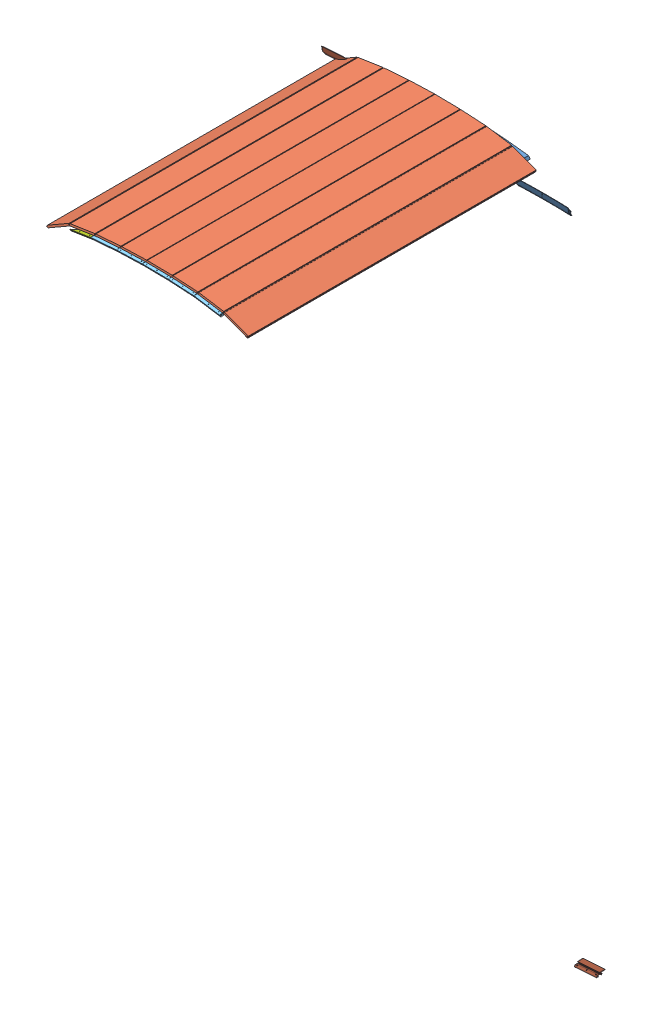
SolidWorks assembly Rear LED Covers, configuration Default. Lengths in mm.
Overall size (2450.92 4696.16 2251.77).
49 component instances, 13 part files, 81 mates.
Components (placement in the parent):
- Rear Ceiling LED Assembly-1: Rear Ceiling LED Assembly [Default] at origin size (1270 56.34 106.68)
- Floor Board-10: Floor Board [Default] at (-117.3306 4.4304 1117.6) x (0.999454 0.033052 0) z (0 0 1) size (195.54 15.11 2133.6)
- Floor Board-11: Floor Board [Default] at (71.8879 6.0598 1117.6) x (0.999875 -0.015835 0) z (0 0 1) size (195.54 15.11 2133.6)
- Floor Board-12: Floor Board [Default] at (262.1828 -1.0885 1117.6) x (0.998261 -0.058943 0) z (0 0 1) size (195.54 15.11 2133.6)
- Floor Board-13: Floor Board [Default] at (453.3637 -21.8246 1117.6) x (0.987717 -0.156253 0) z (0 0 1) size (195.54 15.11 2133.6)
- Floor Board-14: Floor Board [Default] at (-307.4744 -6.0039 1117.6) x (0.99709 0.07623 0) z (0 0 1) size (195.54 15.11 2133.6)
- Floor Board-15: Floor Board [Default] at (-498.2964 -27.9601 1117.6) x (0.988363 0.152114 0) z (0 0 1) size (195.54 15.11 2133.6)
- Floor Board-16: Floor Board [Default] at (638.9233 -71.1917 1117.6) x (0.934506 -0.355948 0) z (0 0 1) size (195.54 15.11 2133.6)
- Floor Board-17: Floor Board [Default] at (-676.3258 -89.879 1117.6) x (0.866563 0.499069 0) z (0 0 1) size (195.54 15.11 2133.6)
- Ceiling LED Mount V1-1: Ceiling LED Mount V1 [Default] at (-574.2075 -55.8979 171.45) x (-0.988363 -0.152114 0) z (0 0 -1) size (29.58 14.17 190.5)
- Ceiling LED Mount V1-2: Ceiling LED Mount V1 [Default] at (530.2435 -50.2519 171.45) x (-0.987717 0.156253 0) z (0 0 -1) size (29.58 14.17 190.5)
- Aclorol LED Neon Rope Lights Addressable LED Strip-1: Aclorol LED Neon Rope Lights Addressable LED Strip [Default] at (133.4826 -131.6632 -32.4083) size (381 11.94 6.05)
- Ceiling LED Mount V1-3: Ceiling LED Mount V1 [Default] at (530.2435 -50.2519 355.6) x (-0.987717 0.156253 0) z (0 0 -1) size (29.58 14.17 190.5)
- Ceiling LED Mount V1-4: Ceiling LED Mount V1 [Default] at (530.2435 -50.2519 539.75) x (-0.987717 0.156253 0) z (0 0 -1) size (29.58 14.17 190.5)
- Ceiling LED Mount V1-5: Ceiling LED Mount V1 [Default] at (530.2435 -50.2519 723.9) x (-0.987717 0.156253 0) z (0 0 -1) size (29.58 14.17 190.5)
- Ceiling LED Mount V1-6: Ceiling LED Mount V1 [Default] at (530.2435 -50.2519 908.05) x (-0.987717 0.156253 0) z (0 0 -1) size (29.58 14.17 190.5)
- Ceiling LED Mount V1-7: Ceiling LED Mount V1 [Default] at (530.2435 -50.2519 1092.2) x (-0.987717 0.156253 0) z (0 0 -1) size (29.58 14.17 190.5)
- Ceiling LED Mount V1-8: Ceiling LED Mount V1 [Default] at (530.2435 -50.2519 1276.35) x (-0.987717 0.156253 0) z (0 0 -1) size (29.58 14.17 190.5)
- Ceiling LED Mount V1-9: Ceiling LED Mount V1 [Default] at (530.2435 -50.2519 1460.5) x (-0.987717 0.156253 0) z (0 0 -1) size (29.58 14.17 190.5)
- Ceiling LED Mount V1-10: Ceiling LED Mount V1 [Default] at (530.2435 -50.2519 1644.65) x (-0.987717 0.156253 0) z (0 0 -1) size (29.58 14.17 190.5)
- Ceiling LED Mount V1-11: Ceiling LED Mount V1 [Default] at (530.2435 -50.2519 1828.8) x (-0.987717 0.156253 0) z (0 0 -1) size (29.58 14.17 190.5)
- Ceiling LED Mount V1-12: Ceiling LED Mount V1 [Default] at (530.2435 -50.2519 2012.95) x (-0.987717 0.156253 0) z (0 0 -1) size (29.58 14.17 190.5)
- Ceiling LED Mount V1-13: Ceiling LED Mount V1 [Default] at (-574.2075 -55.8979 355.6) x (-0.988363 -0.152114 0) z (0 0 -1) size (29.58 14.17 190.5)
- Ceiling LED Mount V1-14: Ceiling LED Mount V1 [Default] at (-574.2075 -55.8979 539.75) x (-0.988363 -0.152114 0) z (0 0 -1) size (29.58 14.17 190.5)
- Ceiling LED Mount V1-15: Ceiling LED Mount V1 [Default] at (-574.2075 -55.8979 723.9) x (-0.988363 -0.152114 0) z (0 0 -1) size (29.58 14.17 190.5)
- Ceiling LED Mount V1-16: Ceiling LED Mount V1 [Default] at (-574.2075 -55.8979 908.05) x (-0.988363 -0.152114 0) z (0 0 -1) size (29.58 14.17 190.5)
- Ceiling LED Mount V1-17: Ceiling LED Mount V1 [Default] at (-574.2075 -55.8979 1092.2) x (-0.988363 -0.152114 0) z (0 0 -1) size (29.58 14.17 190.5)
- Ceiling LED Mount V1-18: Ceiling LED Mount V1 [Default] at (-574.2075 -55.8979 1276.35) x (-0.988363 -0.152114 0) z (0 0 -1) size (29.58 14.17 190.5)
- Ceiling LED Mount V1-19: Ceiling LED Mount V1 [Default] at (-574.2075 -55.8979 1460.5) x (-0.988363 -0.152114 0) z (0 0 -1) size (29.58 14.17 190.5)
- Ceiling LED Mount V1-20: Ceiling LED Mount V1 [Default] at (-574.2075 -55.8979 1644.65) x (-0.988363 -0.152114 0) z (0 0 -1) size (29.58 14.17 190.5)
- Ceiling LED Mount V1-21: Ceiling LED Mount V1 [Default] at (-574.2075 -55.8979 1828.8) x (-0.988363 -0.152114 0) z (0 0 -1) size (29.58 14.17 190.5)
- Ceiling LED Mount V2-6: Ceiling LED Mount V2 [Default] at (447.6359 -37.1838 2194.8666) x (0 0 -1) z (0.987717 -0.156253 0) size (29.58 14.17 196.85)
- Ceiling LED Mount Tee End V2-1: Ceiling LED Mount Tee End V2 [Default] at (530.2435 -50.2519 2197.1) x (-0.987717 0.156253 0) z (0 0 -1) size (29.58 16.09 90.97)
- Ceiling LED Mount V2-7: Ceiling LED Mount V2 [Default] at (257.5107 -16.9061 2194.8666) x (0 0 -1) z (0.998261 -0.058943 0) size (29.58 14.17 196.85)
- Ceiling LED Mount V2-8: Ceiling LED Mount V2 [Default] at (66.5588 -9.9233 2194.8666) x (0 0 -1) z (0.999875 -0.015835 0) size (29.58 14.17 196.85)
- Ceiling LED Mount V2-9: Ceiling LED Mount V2 [Default] at (-124.5339 -11.8821 2194.8666) x (0 0 -1) z (0.999454 0.033052 0) size (29.58 14.17 196.85)
- Ceiling LED Mount V2-10: Ceiling LED Mount V2 [Default] at (-315.3118 -22.7155 2194.8666) x (0 0 -1) z (0.99709 0.07623 0) size (29.58 14.17 196.85)
- Ceiling LED Mount End Stop V3-6: Ceiling LED Mount End Stop V3 [Default] at (-505.1671 -45.2722 2194.8666) x (0 0 -1) z (0.988363 0.152114 0) size (29.58 14.79 160.66)
- Ceiling LED Mount Slant End V2-1: Ceiling LED Mount Slant End V2 [Default] at (-574.2075 -55.8979 2013.331) x (-0.988363 -0.152114 0) z (0 0 -1) size (26.62 14.17 148.49)
- Rear Ceiling LED Strip Mount Base V3-4: Rear Ceiling LED Strip Mount Base V3 [Default] at origin size (201.29 64.14 27.55) (hidden)
- Part3^Rear LED Covers-1: Part3^Rear LED Covers [Default] at origin size (1248.88 52.97 11.2) (virtual)
- Rear Ceiling LED Strip Mount Base V3-5: Rear Ceiling LED Strip Mount Base V3 [Default] at (724.4989 -286.5116 -143.1879) size (201.29 64.14 27.55)
- Rear Ceiling LED Strip Mount Base V3-6: Rear Ceiling LED Strip Mount Base V3 [Default] at (919.954 -290.3755 -143.1879) x (0.999225 -0.039373 0) z (0 0 1) size (201.29 64.14 27.55)
- Rear Ceiling LED Strip Mount 3 V3-13: Rear Ceiling LED Strip Mount 3 V3 [Default] at (0 0 0.1905) size (201.22 64.14 27.55)
- Rear Ceiling LED Strip Mount 1 V3-12: Rear Ceiling LED Strip Mount 1 V3 [Default] at (-386.5352 -15.1012 0.1905) x (0.996952 0.078017 0) z (0 0 1) size (197.53 63.99 27.55)
- Rear Ceiling LED Strip Mount 2 V3-14: Rear Ceiling LED Strip Mount 2 V3 [Default] at (-195.4593 -3.857 0.1905) x (0.999222 0.039451 0) z (0 0 1) size (197.2 63.97 27.55)
- Rear Ceiling LED Strip Mount 3 V3-14: Rear Ceiling LED Strip Mount 3 V3 [Default] at (405.5864 -16.6291 0.1905) x (0.996644 -0.081862 0) z (0 0 1) size (201.22 64.14 27.55)
- Rear Ceiling LED Strip Mount 3 V3-9: Rear Ceiling LED Strip Mount 3 V3 [Default] at (1641.793 -4736.1556 412.2099) x (0.968729 0.192891 0.156066) z (-0.195284 0.980747 0) size (201.22 64.14 27.55)
- Rear Ceiling LED Strip Mount 3 V3-15: Rear Ceiling LED Strip Mount 3 V3 [Default] at (-627.2328 -67.3178 -60.0764) x (0.999206 0.03983 0) z (0 0 1) size (201.22 64.14 27.55)
Mates (geometry in assembly coordinates):
- InPlace1: in place: plane of ? through (0 0 0) normal (0 0 1); moOrthogonalPlaneRef_w of ? through (0 0 0) normal (0 1 0); plane of ? through (0 0 0) normal (1 0 0); unknown of ?
- Coincident14: coincident aligned: plane of assembly through (0 0 0) normal (0 0 1)
- Coincident15: coincident aligned: plane of Part7^Rear LED Covers-1 through (0 0 0) normal (0 1 0)
- Coincident16: coincident anti-aligned: plane of Part7^Rear LED Covers-1 through (0 0 0) normal (1 0 0)
- Coincident1: coincident: point of ?; point of Floor Board-10
- Coincident2: coincident: point of ?; point of Floor Board-14
- Coincident3: coincident: point of ?; point of Floor Board-15
- Coincident4: coincident: point of ?; point of Floor Board-12
- Coincident5: coincident: point of ?; point of Floor Board-11
- Coincident6: coincident: point of ?; point of Floor Board-13
- Coincident7: coincident aligned: line of Rear Ceiling LED Assembly-1 through (192.2026 357.2621 -14.2722) axis (0 0.987717 -0.156253); line of Floor Board-13 through (189.0649 358.8117 -14.5173) axis (0 0.987717 -0.156253)
- Coincident9: coincident aligned: line of Rear Ceiling LED Assembly-1 through (191.3822 166.2126 -2.9915) axis (0 0.998261 -0.058943); line of Floor Board-12 through (189.0649 167.3693 -3.0598) axis (0 0.998261 -0.058943)
- Coincident10: coincident aligned: line of Rear Ceiling LED Assembly-1 through (188.9125 -22.6762 0) axis (0 0.999875 -0.015835); line of Floor Board-11 through (-22.7524 0.0012 0) axis (0.999875 -0.015835 0)
- Coincident11: coincident anti-aligned: line of Rear Ceiling LED Assembly-1 through (188.9125 -22.6762 0) axis (0 -0.999454 -0.033052); line of Floor Board-10 through (189.0649 -211.5616 -6.2464) axis (0 0.999454 0.033052)
- Coincident12: coincident anti-aligned: line of Rear Ceiling LED Assembly-1 through (191.3826 -211.4855 -6.2439) axis (0 -0.99709 -0.07623); line of Floor Board-14 through (189.0649 -401.1557 -20.7446) axis (0 0.99709 0.07623)
- Coincident13: coincident anti-aligned: line of Rear Ceiling LED Assembly-1 through (191.9046 -402.3112 -20.833) axis (0 -0.988363 -0.152114); line of Floor Board-15 through (189.0649 -590.5793 -49.8084) axis (0 0.988363 0.152114)
- Coincident14: coincident aligned: line of Rear Ceiling LED Assembly-1 through (199.9255 547.1039 -44.3043) axis (0 0.934506 -0.355948); line of Floor Board-16 through (547.8925 -44.6047 0) axis (0.934506 -0.355948 0)
- Coincident15: coincident aligned: plane of Floor Board-13 through (453.3637 -21.8246 2184.4) normal (0 0 1); plane of Floor Board-16 through (638.9233 -71.1917 2184.4) normal (0 0 1)
- Coincident16: coincident anti-aligned: line of Rear Ceiling LED Assembly-1 through (222.3993 -591.9826 -50.0244) axis (0 -0.866563 -0.499069); line of Floor Board-17 through (189.0649 -754.4729 -143.6054) axis (0 0.866563 0.499069)
- Coincident17: coincident aligned: plane of Floor Board-15 through (-498.2964 -27.9601 2184.4) normal (0 0 1); plane of Floor Board-17 through (-676.3258 -89.879 2184.4) normal (0 0 1)
- Coincident18: coincident aligned: plane of Floor Board-14 through (-307.4744 -6.0039 2184.4) normal (0 0 1); plane of Floor Board-15 through (-498.2964 -27.9601 2184.4) normal (0 0 1)
- Coincident19: coincident aligned: plane of Floor Board-10 through (-117.3306 4.4304 2184.4) normal (0 0 1); plane of Floor Board-14 through (-307.4744 -6.0039 2184.4) normal (0 0 1)
- Coincident21: coincident aligned: plane of Floor Board-10 through (-117.3306 4.4304 2184.4) normal (0 0 1); plane of Floor Board-11 through (71.8879 6.0598 2184.4) normal (0 0 1)
- Coincident22: coincident aligned: plane of Floor Board-11 through (71.8879 6.0598 2184.4) normal (0 0 1); plane of Floor Board-12 through (262.1828 -1.0885 2184.4) normal (0 0 1)
- Distance1: distance = 1.27 mm: line of Floor Board-15 through (-591.3035 -49.2774 2184.4) axis (0 0 -1); line of Floor Board-17 through (-590.403 -48.3819 2184.4) axis (0 0 -1)
- Coincident24: coincident anti-aligned: plane of Floor Board-15 through (-497.1469 -35.4287 2184.4) normal (0.152114 -0.988363 0); plane of Ceiling LED Mount V1-1 through (-575.5018 -47.4879 76.2) normal (-0.152114 0.988363 0)
- Parallel3: parallel anti-aligned: plane of Floor Board-15 through (-498.2964 -27.9601 2184.4) normal (0 0 1); plane of Ceiling LED Mount V1-1 through (-574.2075 -55.8979 82.55) normal (0 0 -1)
- Distance2: distance = 1.27 mm: line of Floor Board-15 through (-591.3035 -49.2774 2184.4) axis (0 0 -1); line of Ceiling LED Mount V1-1 through (-590.1198 -49.7377 76.2) axis (0 0 1)
- Coincident27: coincident anti-aligned: plane of Floor Board-13 through (452.183 -29.2883 2184.4) normal (-0.156253 -0.987717 0); plane of Ceiling LED Mount V1-2 through (531.5731 -41.8474 76.2) normal (0.156253 0.987717 0)
- Distance3: distance = 1.27 mm: line of Floor Board-16 through (547.5251 -43.7853 2184.4) axis (0 0 -1); line of Floor Board-13 through (546.2808 -43.5312 2184.4) axis (0 0 -1)
- Coincident38: coincident anti-aligned: plane of Ceiling LED Mount V1-12 through (530.2435 -50.2519 2108.2) normal (0 0 1); plane of Ceiling LED Mount Tee End V1-1 through (530.2435 -50.2519 2108.2) normal (0 0 -1)
- Coincident39: coincident aligned: plane of Ceiling LED Mount V1-12 through (531.5731 -41.8474 1917.7) normal (0.156253 0.987717 0); plane of Ceiling LED Mount Tee End V1-1 through (531.5731 -41.8474 2101.85) normal (0.156253 0.987717 0)
- Concentric1: concentric anti-aligned: cylinder of Ceiling LED Mount V1-12 through (531.5731 -41.8474 2102.231) axis (0 0 1) radius 12.5042; cylinder of Ceiling LED Mount Tee End V1-1 through (531.5731 -41.8474 2108.2) axis (0 0 -1) radius 12.8852
- Concentric2: concentric aligned: cylinder of Ceiling LED Mount V2-1 through (546.1815 -44.1584 2194.8666) axis (-0.987717 0.156253 0) radius 14.7902; cylinder of Ceiling LED Mount Tee End V1-1 through (546.1815 -44.1584 2194.8666) axis (-0.987717 0.156253 0) radius 15.1638
- Coincident40: coincident aligned: plane of Ceiling LED Mount V2-1 through (546.1815 -44.1584 2194.8666) normal (0.156253 0.987717 0); plane of Ceiling LED Mount Tee End V1-1 through (531.5731 -41.8474 2101.85) normal (0.156253 0.987717 0)
- Distance4: distance = 2006.6 mm aligned: plane of Ceiling LED Mount V1-12 through (530.2435 -50.2519 2108.2) normal (0 0 1); plane of Rear Ceiling LED Assembly-1 through (0 -4954.4862 101.6) normal (0 0 1)
- Coincident43: coincident anti-aligned: plane of Floor Board-12 through (261.7374 -8.6319 2184.4) normal (-0.058943 -0.998261 0); plane of Ceiling LED Mount V2-2 through (356.2662 -14.2134 2194.8666) normal (0.058943 0.998261 0)
- Coincident44: coincident: plane of Ceiling LED Mount V2-1 through (356.3156 -22.7373 2194.8666) normal (-0.987717 0.156253 0); point of Ceiling LED Mount V2-2
- Coincident45: coincident aligned: plane of Ceiling LED Mount V2-1 through (544.852 -52.5629 2198.0797) normal (0 0 -1); plane of Ceiling LED Mount V2-2 through (355.7646 -22.7076 2198.0797) normal (0 0 -1)
- Coincident46: coincident anti-aligned: plane of Floor Board-11 through (71.7682 -1.4958 2184.4) normal (-0.015835 -0.999875 0); plane of Ceiling LED Mount V2-3 through (165.1062 -2.974 2194.8666) normal (0.015835 0.999875 0)
- Coincident47: coincident anti-aligned: plane of Floor Board-10 through (-117.0808 -3.1219 2184.4) normal (0.033052 -0.999454 0); plane of Ceiling LED Mount V2-4 through (-26.4439 -0.1246 2194.8666) normal (-0.033052 0.999454 0)
- Coincident48: coincident aligned: plane of Ceiling LED Mount V2-2 through (355.7646 -22.7076 2198.0797) normal (0 0 -1); plane of Ceiling LED Mount V2-3 through (164.9715 -11.4819 2198.0797) normal (0 0 -1)
- Coincident49: coincident aligned: plane of Ceiling LED Mount V2-3 through (164.9715 -11.4819 2198.0797) normal (0 0 -1); plane of Ceiling LED Mount V2-4 through (-26.1627 -8.629 2198.0797) normal (0 0 -1)
- Coincident50: coincident: plane of Ceiling LED Mount V2-2 through (165.2155 -11.4564 2194.8666) normal (-0.998261 0.058943 0); point of Ceiling LED Mount V2-3
- Coincident51: coincident: plane of Ceiling LED Mount V2-3 through (-25.8856 -8.4592 2194.8666) normal (-0.999875 0.015835 0); point of Ceiling LED Mount V2-4
- Coincident52: coincident anti-aligned: line of Ceiling LED Mount V2-1 through (546.1815 -44.1584 2181.9814) axis (0 0 -1); line of Ceiling LED Mount Tee End V1-1 through (546.1815 -44.1584 2101.85) axis (0 0 1)
- Coincident53: coincident anti-aligned: plane of Floor Board-14 through (-306.8983 -13.5384 2184.4) normal (0.07623 -0.99709 0); plane of Ceiling LED Mount V2-5 through (-217.8218 -6.7283 2194.8666) normal (-0.07623 0.99709 0)
- Coincident54: coincident: plane of Ceiling LED Mount V2-4 through (-216.9394 -14.9379 2194.8666) normal (-0.999454 -0.033052 0); point of Ceiling LED Mount V2-5
- Coincident55: coincident aligned: plane of Ceiling LED Mount V2-4 through (-26.1627 -8.629 2198.0797) normal (0 0 -1); plane of Ceiling LED Mount V2-5 through (-217.1732 -15.2126 2198.0797) normal (0 0 -1)
- Coincident56: coincident anti-aligned: plane of Floor Board-15 through (-497.1469 -35.4287 2184.4) normal (0.152114 -0.988363 0); plane of Ceiling LED Mount End Stop V3-6 through (-409.1818 -21.8904 2194.8666) normal (-0.152114 0.988363 0)
- Coincident57: coincident aligned: plane of Ceiling LED Mount V2-10 through (-217.1732 -15.2126 2191.6535) normal (0 0 1); plane of Ceiling LED Mount End Stop V3-6 through (-407.8874 -30.3004 2191.6535) normal (0 0 1)
- Coincident58: coincident: plane of Ceiling LED Mount V2-10 through (-407.4987 -29.7634 2194.8666) normal (-0.99709 -0.07623 0); point of Ceiling LED Mount End Stop V3-6
- Coincident59: coincident: plane of Floor Board-13 through (547.3623 -36.6947 2184.4) normal (0.987717 -0.156253 0); line of Ceiling LED Mount V1-2 through (546.1815 -44.1584 76.2) axis (0 0 1)
- Concentric3: concentric: cylinder of Ceiling LED Mount V1-21 through (-575.5018 -47.4879 1918.081) axis (0 0 1) radius 12.5042; cylinder of Ceiling LED Mount Tee End V2-2 through (-575.5018 -47.4879 1905.251) axis (0 0 -1) radius 12.8852
- Coincident60: coincident: plane of Ceiling LED Mount V1-21 through (-574.2075 -55.8979 1924.05) normal (0 0 1); plane of Ceiling LED Mount Tee End V2-2 through (-574.2075 -55.8979 1905.251) normal (0 0 -1)
- Coincident61: coincident aligned: plane of Ceiling LED Mount V1-21 through (-575.5018 -47.4879 1733.55) normal (-0.152114 0.988363 0); plane of Ceiling LED Mount Tee End V2-2 through (-575.5018 -47.4879 1898.901) normal (-0.152114 0.988363 0)
- Concentric4: concentric anti-aligned: cylinder of Ceiling LED Mount V1-21 through (-575.5018 -47.4879 1918.081) axis (0 0 1) radius 12.5042; cylinder of Ceiling LED Mount Slant End V2-1 through (-575.5018 -47.4879 1924.431) axis (0 0 -1) radius 12.8852
- Coincident62: coincident aligned: plane of Ceiling LED Mount V1-21 through (-575.5018 -47.4879 1733.55) normal (-0.152114 0.988363 0); plane of Ceiling LED Mount Slant End V2-1 through (-575.5018 -47.4879 1918.081) normal (-0.152114 0.988363 0)
- Coincident63: coincident aligned: plane of Ceiling LED Mount V1-1 through (-574.2075 -55.8979 82.55) normal (0 0 -1); plane of Ceiling LED Mount V1-2 through (530.2435 -50.2519 82.55) normal (0 0 -1)
- Coincident64: coincident anti-aligned: plane of Ceiling LED Mount V1-21 through (-574.2075 -55.8979 1918.081) normal (0 0 1); plane of Ceiling LED Mount Slant End V2-1 through (-574.2075 -55.8979 1918.081) normal (0 0 -1)
- Distance5: distance = 0.381 mm anti-aligned: plane of Rear Ceiling LED Strip Mount Base V3-2 through (701.8994 -286.6147 -143.1879) normal (0.99999 0.004561 0); plane of Rear Ceiling LED Strip Mount Base V3-3 through (702.4051 -313.9657 -22.1507) normal (-0.99999 -0.004561 0)
- Coincident65: coincident aligned: plane of Rear Ceiling LED Strip Mount Base V3-2 through (103.7103 -379.2866 -41.3974) normal (0 0 -1); plane of Rear Ceiling LED Strip Mount Base V3-3 through (295.994 -358.6362 -41.3974) normal (0 0 -1)
- Concentric5: concentric aligned: cylinder of Rear Ceiling LED Assembly-1 through (0 -4954.4862 106.68) axis (0 0 -1) radius 4901.3755; cylinder of Rear Ceiling LED Strip Mount 2 V3-14 through (0 -4954.4862 101.7905) axis (0 0 -1) radius 4901.185
- Distance6: distance = 0.381 mm anti-aligned: plane of Rear Ceiling LED Assembly-1 through (0 -4954.4862 106.68) normal (0 0 1); plane of Rear Ceiling LED Strip Mount 2 V3-14 through (-812.994 -116.0488 107.061) normal (0 0 -1)
- Distance7: distance = 0.381 mm anti-aligned: plane of Rear Ceiling LED Assembly-1 through (0 -4954.4862 106.68) normal (0 0 1); plane of Rear Ceiling LED Strip Mount 3 V3-1 through (-1501.7865 -283.7183 107.061) normal (0 0 -1)
- Concentric6: concentric aligned: cylinder of Rear Ceiling LED Assembly-1 through (0 -4954.4862 106.68) axis (0 0 -1) radius 4901.3755; cylinder of Rear Ceiling LED Strip Mount 3 V3-1 through (0 -4954.4862 101.7905) axis (0 0 -1) radius 4901.185
- Distance8: distance = 0.381 mm anti-aligned: plane of Rear Ceiling LED Assembly-1 through (0 -4954.4862 106.68) normal (0 0 1); plane of Rear Ceiling LED Strip Mount 3 V3-13 through (-621.48 -87.7421 107.061) normal (0 0 -1)
- Concentric7: concentric aligned: cylinder of Rear Ceiling LED Assembly-1 through (0 -4954.4862 106.68) axis (0 0 -1) radius 4901.3755; cylinder of Rear Ceiling LED Strip Mount 3 V3-13 through (0 -4954.4862 101.7905) axis (0 0 -1) radius 4901.185
- Concentric8: concentric aligned: cylinder of Rear Ceiling LED Assembly-1 through (0 -4954.4862 106.68) axis (0 0 -1) radius 4901.3755; cylinder of Rear Ceiling LED Strip Mount 1 V3-12 through (0 -4954.4862 101.7905) axis (0 0 -1) radius 4901.185
- Distance9: distance = 0.381 mm anti-aligned: plane of Rear Ceiling LED Assembly-1 through (0 -4954.4862 106.68) normal (0 0 1); plane of Rear Ceiling LED Strip Mount 3 V3-3 through (-999.2755 -151.062 107.061) normal (0 0 -1)
- Concentric9: concentric aligned: cylinder of Rear Ceiling LED Assembly-1 through (0 -4954.4862 106.68) axis (0 0 -1) radius 4901.3755; cylinder of Rear Ceiling LED Strip Mount 4 V3-10 through (0 -4954.4862 101.7905) axis (0 0 -1) radius 4901.185
- Distance12: distance = 0.381 mm anti-aligned: plane of Rear Ceiling LED Assembly-1 through (0 -4954.4862 106.68) normal (0 0 1); plane of Rear Ceiling LED Strip Mount 3 V3-4 through (-429.0684 -67.019 107.061) normal (0 0 -1)
- Concentric10: concentric aligned: cylinder of Rear Ceiling LED Assembly-1 through (0 -4954.4862 106.68) axis (0 0 -1) radius 4901.3755; cylinder of Rear Ceiling LED Strip Mount 3 V3-14 through (0 -4954.4862 101.7905) axis (0 0 -1) radius 4901.185
- Distance13: distance = 0.381 mm anti-aligned: plane of Rear Ceiling LED Assembly-1 through (0 -4954.4862 106.68) normal (0 0 1); plane of Rear Ceiling LED Strip Mount 3 V3-14 through (-220.9904 -53.2008 107.061) normal (0 0 -1)
- Coincident71: coincident aligned: plane of Floor Board-10 through (-117.3306 4.4304 1117.6) normal (0.999454 0.033052 0); plane of Rear Ceiling LED Strip Mount 3 V3-13 through (-117.056 -3.871 0.1905) normal (0.999454 0.033052 0)
- Distance15: distance = 0.381 mm: point of Rear Ceiling LED Strip Mount 3 V3-13; plane of Rear Ceiling LED Strip Mount 2 V3-14 through (-209.6473 -59.9453 110.4912) normal (0.999084 0.042794 0)
- Distance16: distance = 0.381 mm: point of Rear Ceiling LED Strip Mount 3 V3-12; plane of Rear Ceiling LED Strip Mount 2 V3-14 through (-402.32 -20.7253 0.1905) normal (-0.996692 -0.081275 0)
- Distance18: distance = 0.381 mm: point of Rear Ceiling LED Strip Mount 4 V3-10; plane of Rear Ceiling LED Strip Mount 3 V3-14 through (194.1139 -8.3297 0.1905) normal (-0.999231 0.039215 0)
- Concentric11: concentric aligned: cylinder of Rear Ceiling LED Assembly-1 through (0 -4954.4862 106.68) axis (0 0 -1) radius 4901.3755; cylinder of Rear Ceiling LED Strip Mount 4 V3-1 through (0 -4954.4862 101.7905) axis (0 0 -1) radius 4901.185
- Distance20: distance = 0.381 mm: cylinder of Rear Ceiling LED Assembly-1 through (0 -4954.4862 106.68) axis (0 0 -1) radius 4901.3755; plane of Rear Ceiling LED Strip Mount 3 V3-9 through (1005.4471 -4753.8951 401.8849) normal (0.195284 -0.980747 0)
- Distance21: distance = 0.381 mm anti-aligned: plane of Rear Ceiling LED Assembly-1 through (0 -4954.4862 106.68) normal (0 0 1); plane of Rear Ceiling LED Strip Mount 4 V3-1 through (-429.0684 -67.019 107.061) normal (0 0 -1)
